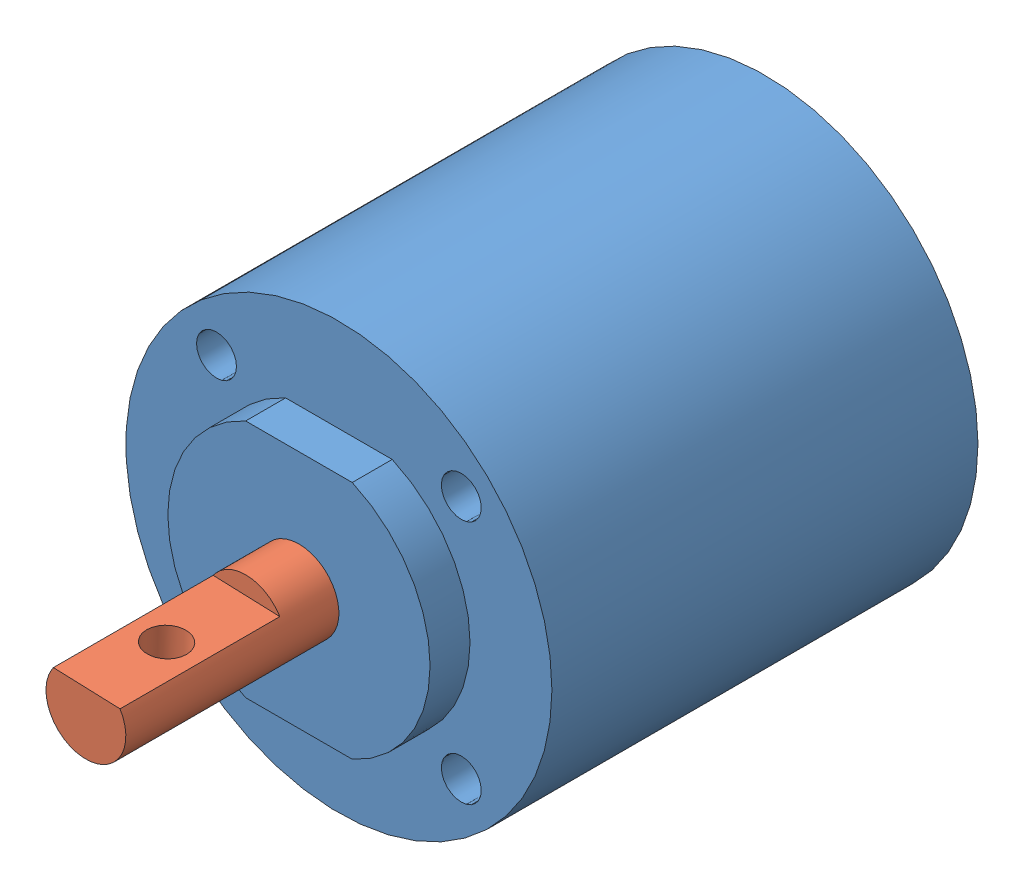
SolidWorks assembly Assem1, configuration Default. Lengths in mm.
Overall size (32 32 51).
2 component instances, 2 part files, 1 mates.
Components (placement in the parent):
- Encoder-2: Encoder [Default] at (-0.2706 -6.941 -0.6916) size (32 32 35)
- Motor_shaftV2-2: Motor_shaftV2 [Default] at (-0.2706 -6.941 2.3084) x (0.999342 -0.036274 0) z (0 0 1) size (6 6 16)
Mates (geometry in assembly coordinates):
- Coincident4: coincident aligned: circle of Encoder-2; circle of Motor_shaftV2-2
